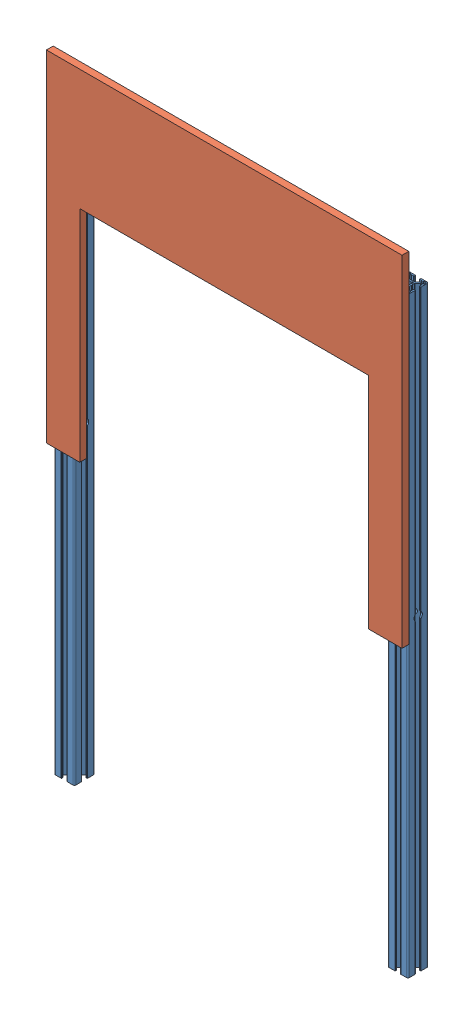
SolidWorks assembly Handz, configuration Default. Lengths in mm.
Overall size (522.3 925.5 40).
3 component instances, 2 part files, 8 mates.
Components (placement in the parent):
- 8020-30-3030-30-3030 X 4 M-1: 8020-30-3030-30-3030 X 4 M [Default] at (110.6415 -3045.9445 556.6015) size (30 870 30)
- 8020-30-3030-30-3030 X 4 M-2: 8020-30-3030-30-3030 X 4 M [Default] at (600.5416 -3045.9445 556.6015) size (30 870 30)
- Poygal-1: Poygal [Default] at (904.0582 509.5555 609.9819) x (0 0 -1) z (1 0 0) size (10 500 522.3)
Mates (geometry in assembly coordinates):
- Distance7: distance = 519.9 mm: point of 8020-30-3030-30-3030 X 4 M-1; point of 8020-30-3030-30-3030 X 4 M-2
- Parallel8: parallel aligned: line of 8020-30-3030-30-3030 X 4 M-2 through (902.8522 954.0555 597.9819) axis (0 -1 0); line of Poygal-1 through (904.0582 1009.5555 599.9819) axis (0 -1 0)
- Coincident36: coincident anti-aligned: plane of 8020-30-3030-30-3030 X 4 M-2 through (892.3522 954.0555 599.9819) normal (0 0 1); plane of Poygal-1 through (904.0582 509.5555 599.9819) normal (0 0 -1)
- Coincident37: coincident anti-aligned: plane of 8020-30-3030-30-3030 X 4 M-1 through (384.9521 954.0555 599.9819) normal (0 0 1); plane of Poygal-1 through (904.0582 509.5555 599.9819) normal (0 0 -1)
- Distance18: distance = 55.5 mm aligned: plane of Poygal-1 through (904.0582 1009.5555 599.9819) normal (0 1 0); plane of 8020-30-3030-30-3030 X 4 M-2 through (901.0947 954.0555 589.4819) normal (0 1 0)
- Distance19: distance = 55.5 mm aligned: plane of Poygal-1 through (904.0582 1009.5555 599.9819) normal (0 1 0); plane of 8020-30-3030-30-3030 X 4 M-1 through (411.1946 954.0555 589.4819) normal (0 1 0)
- Coincident42: coincident anti-aligned: plane of Poygal-1 through (904.0582 509.5555 599.9819) normal (0 0 -1); plane of 8020-30-3030-30-3030 X 4 M-1 through (384.9521 954.0555 599.9819) normal (0 0 1)
- Coincident43: coincident anti-aligned: plane of Poygal-1 through (904.0582 509.5555 599.9819) normal (0 0 -1); plane of 8020-30-3030-30-3030 X 4 M-2 through (874.8523 954.0555 599.9819) normal (0 0 1)
